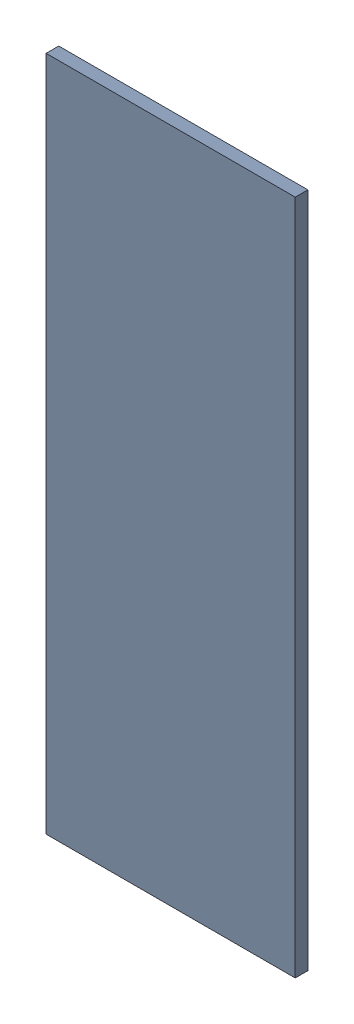
SolidWorks assembly Pad RAK4600-19(23.725mm,8.691mm) on Top Layer, configuration Predeterminado. Lengths in mm.
Overall size (0.7 1.9 0.04).
2 component instances, 1 part files, 0 mates.
Components (placement in the parent):
- Pad RAK4600-19(23.725mm,8.691mm) on Top Layer-1-1: Pad RAK4600-19(23.725mm,8.691mm) on Top Layer-1 [Predeterminado] at (-68.317 -44.187 -0.0457) size (0.7 1.9 0.04)
  - Pad RAK4600-19(23.725mm,8.691mm) on Top Layer-Part-1-1: Pad RAK4600-19(23.725mm,8.691mm) on Top Layer-Part-1 [Predeterminado] at origin size (0.7 1.9 0.04)
